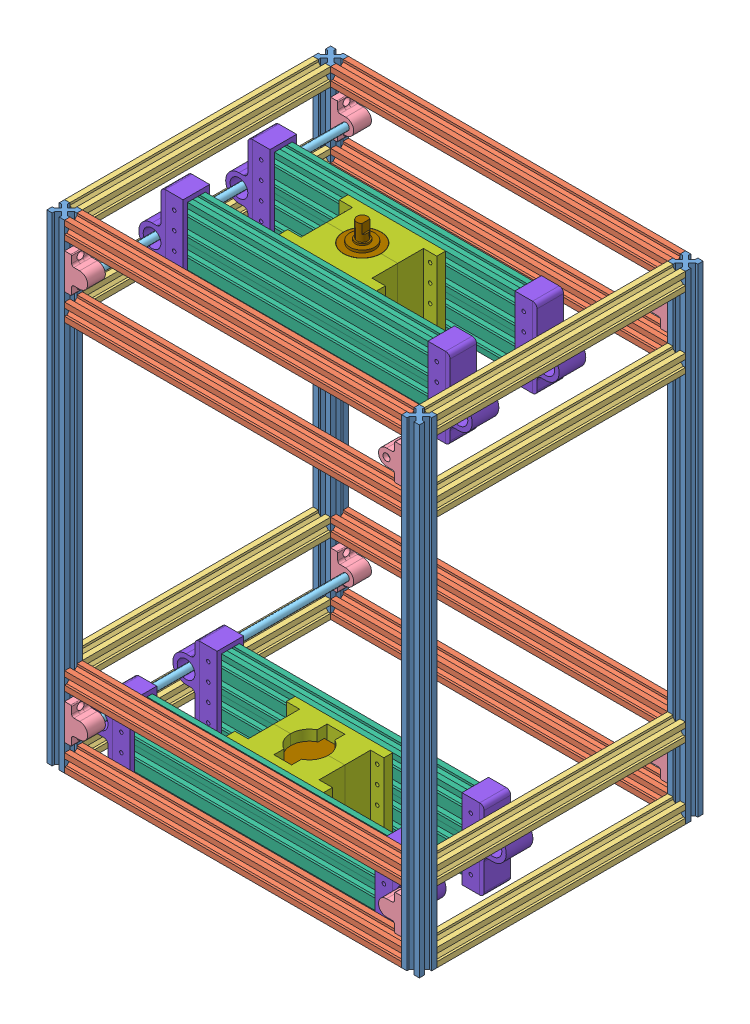
SolidWorks assembly chassis complété 1.1, configuration Défaut. Lengths in mm.
Overall size (420 586 320).
61 component instances, 9 part files, 54 mates.
Components (placement in the parent):
- module externe1.0-1: module externe1.0 [Défaut] at origin size (420 540 320)
  - base chassis horizontale-1: base chassis horizontale [Défaut] at (107.5488 34.6411 0) size (420 540 20)
    - profilé 540-1: profilé 540 [Défaut] at (-152.6624 -292.9685 550) size (20 540 20)
    - profilé 380-1: profilé 380 [Défaut] at (-152.6624 -272.9685 550) x (0 0 1) z (0 1 0) size (20 380 20)
    - profilé 380-2: profilé 380 [Défaut] at (227.3376 -212.9685 550) x (0 0 1) z (0 -1 0) size (20 380 20)
    - profilé 380-3: profilé 380 [Défaut] at (227.3376 227.0315 550) x (0 0 1) z (0 -1 0) size (20 380 20)
    - profilé 380-4: profilé 380 [Défaut] at (227.3376 147.0315 550) x (0 0 1) z (0 -1 0) size (20 380 20)
    - profilé 540-2: profilé 540 [Défaut] at (247.3376 -292.9685 530) x (0 0 -1) z (1 0 0) size (20 540 20)
  - profilé 280-1: profilé 280 [Défaut] at (-45.1136 -238.3275 550) x (0 1 0) z (1 0 0) size (20 280 20)
  - profilé 280-2: profilé 280 [Défaut] at (334.8864 -258.3275 830) x (-1 0 0) z (0 -1 0) size (20 280 20)
  - profilé 280-3: profilé 280 [Défaut] at (334.8864 281.6725 550) x (-1 0 0) z (0 1 0) size (20 280 20)
  - profilé 280-4: profilé 280 [Défaut] at (-65.1136 281.6725 550) x (-1 0 0) z (0 1 0) size (20 280 20)
  - base chassis horizontale-2: base chassis horizontale [Défaut] at (182.224 -11.296 300) x (-1 0 0) z (0 0 1) size (420 540 20)
    - profilé 540-1: profilé 540 [Défaut] at (-152.6624 -292.9685 550) size (20 540 20)
    - profilé 380-1: profilé 380 [Défaut] at (-152.6624 -272.9685 550) x (0 0 1) z (0 1 0) size (20 380 20)
    - profilé 380-2: profilé 380 [Défaut] at (227.3376 -212.9685 550) x (0 0 1) z (0 -1 0) size (20 380 20)
    - profilé 380-3: profilé 380 [Défaut] at (227.3376 227.0315 550) x (0 0 1) z (0 -1 0) size (20 380 20)
    - profilé 380-4: profilé 380 [Défaut] at (227.3376 147.0315 550) x (0 0 1) z (0 -1 0) size (20 380 20)
    - profilé 540-2: profilé 540 [Défaut] at (247.3376 -292.9685 530) x (0 0 -1) z (1 0 0) size (20 540 20)
  - profilé 280-5: profilé 280 [Défaut] at (-65.1136 -158.3275 550) x (-1 0 0) z (0 1 0) size (20 280 20)
  - profilé 280-6: profilé 280 [Défaut] at (354.8864 -178.3275 550) x (1 0 0) z (0 -1 0) size (20 280 20)
  - profilé 280-7: profilé 280 [Défaut] at (334.8864 181.6725 830) x (-1 0 0) z (0 -1 0) size (20 280 20)
  - profilé 280-8: profilé 280 [Défaut] at (-45.1136 181.6725 830) x (0 -1 0) z (1 0 0) size (20 280 20)
- support axe 8mm-1: support axe 8mm [Défaut] at (317.8864 -208.3275 850) x (0 -1 0) z (0 0 -1) size (40 26 20)
- support axe 8mm-3: support axe 8mm [Défaut] at (-28.1136 -208.3275 850) x (0 1 0) z (0 0 -1) size (40 26 20)
- support axe 8mm-4: support axe 8mm [Défaut] at (317.8864 -208.3275 530) x (0 1 0) z (0 0 1) size (40 26 20)
- support axe 8mm-5: support axe 8mm [Défaut] at (-28.1136 -208.3275 530) x (0 -1 0) z (0 0 1) size (40 26 20)
- support axe 8mm-6: support axe 8mm [Défaut] at (317.8864 231.6725 530) x (0 1 0) z (0 0 1) size (40 26 20)
- support axe 8mm-7: support axe 8mm [Défaut] at (-28.1136 231.6725 530) x (0 -1 0) z (0 0 1) size (40 26 20)
- support axe 8mm-8: support axe 8mm [Défaut] at (317.8864 231.6725 830) x (0 1 0) z (0 0 1) size (40 26 20)
- support axe 8mm-9: support axe 8mm [Défaut] at (-28.1136 231.6725 850) x (0 1 0) z (0 0 -1) size (40 26 20)
- axe 8mm-1: axe 8mm [Défaut] at (317.8864 -208.3275 535) x (-0.178456 0.983948 0) z (0 0 1) size (8 8 310)
- axe 8mm-2: axe 8mm [Défaut] at (-28.1136 -208.3275 535) size (8 8 310)
- axe 8mm-3: axe 8mm [Défaut] at (-28.1136 231.6725 535) size (8 8 310)
- axe 8mm-4: axe 8mm [Défaut] at (317.8864 231.6725 535) x (0.682458 0.730925 0) z (0 0 1) size (8 8 310)
- suspension1.0-1: suspension1.0 [Défaut] at (152.5638 -155.3507 385) x (0 1 0) z (0 0 1) size (90 376 64)
  - profilé 370-40-1: profilé 370-40 [Défaut] at (-82.9768 -150.3226 340) size (40 316 20)
  - profilé 370-40-2: profilé 370-40 [Défaut] at (-42.9768 -150.3226 340) size (40 316 20)
  - support moteur-2: support moteur [Défaut] at (-47.9768 7.6774 359.5) x (0 -1 0) z (-1 0 0) size (110 39 80)
  - fin profilé-1: fin profilé [Défaut] at (-62.9768 165.6774 330) x (-1 0 0) z (0 -1 0) size (90 30 50)
  - fin profilé-2: fin profilé [Défaut] at (-62.9768 -150.3226 330) x (-1 0 0) z (0 1 0) size (90 30 50)
- suspension1.0-2: suspension1.0 [Défaut] at (137.209 -155.3507 1143) x (0 1 0) z (0 0 -1) size (90 376 64)
  - profilé 370-40-1: profilé 370-40 [Défaut] at (-82.9768 -150.3226 340) size (40 316 20)
  - profilé 370-40-2: profilé 370-40 [Défaut] at (-42.9768 -150.3226 340) size (40 316 20)
  - support moteur-2: support moteur [Défaut] at (-47.9768 7.6774 359.5) x (0 -1 0) z (-1 0 0) size (110 39 80)
  - fin profilé-1: fin profilé [Défaut] at (-62.9768 165.6774 330) x (-1 0 0) z (0 -1 0) size (90 30 50)
  - fin profilé-2: fin profilé [Défaut] at (-62.9768 -150.3226 330) x (-1 0 0) z (0 1 0) size (90 30 50)
- moteur-1: moteur [Défaut] at (144.8864 -189.9275 764) x (1 0 0) z (0 -1 0) size (42 47 91.4)
- suspension1.0-3: suspension1.0 [Défaut] at (137.209 178.6957 325.3692) x (0 -1 0) z (0 0 1) size (90 376 64)
  - profilé 370-40-1: profilé 370-40 [Défaut] at (-82.9768 -150.3226 340) size (40 316 20)
  - profilé 370-40-2: profilé 370-40 [Défaut] at (-42.9768 -150.3226 340) size (40 316 20)
  - support moteur-2: support moteur [Défaut] at (-47.9768 7.6774 359.5) x (0 -1 0) z (-1 0 0) size (110 39 80)
  - fin profilé-1: fin profilé [Défaut] at (-62.9768 165.6774 330) x (-1 0 0) z (0 -1 0) size (90 30 50)
  - fin profilé-2: fin profilé [Défaut] at (-62.9768 -150.3226 330) x (-1 0 0) z (0 1 0) size (90 30 50)
- suspension1.0-4: suspension1.0 [Défaut] at (152.5638 178.6957 1083.3692) x (0 -1 0) z (0 0 -1) size (90 376 64)
  - profilé 370-40-1: profilé 370-40 [Défaut] at (-82.9768 -150.3226 340) size (40 316 20)
  - profilé 370-40-2: profilé 370-40 [Défaut] at (-42.9768 -150.3226 340) size (40 316 20)
  - support moteur-2: support moteur [Défaut] at (-47.9768 7.6774 359.5) x (0 -1 0) z (-1 0 0) size (110 39 80)
  - fin profilé-1: fin profilé [Défaut] at (-62.9768 165.6774 330) x (-1 0 0) z (0 -1 0) size (90 30 50)
  - fin profilé-2: fin profilé [Défaut] at (-62.9768 -150.3226 330) x (-1 0 0) z (0 1 0) size (90 30 50)
- moteur-2: moteur [Défaut] at (144.8864 213.2725 704.3692) x (-1 0 0) z (0 1 0) size (42 47 91.4)
Mates (geometry in assembly coordinates):
- Coïncidente1: coincident anti-aligned: plane of module externe1.0-1/base chassis horizontale-2/profilé 540-1 through (334.8864 -258.3275 850) normal (-1 0 0); plane of support axe 8mm-1 through (334.8864 -208.3275 830) normal (1 0 0)
- Coïncidente4: coincident anti-aligned: plane of module externe1.0-1/base chassis horizontale-2/profilé 540-2 through (-45.1136 -258.3275 830) normal (1 0 0); plane of support axe 8mm-3 through (-45.1136 -208.3275 830) normal (-1 0 0)
- Coïncidente7: coincident anti-aligned: plane of module externe1.0-1/base chassis horizontale-1/profilé 540-2 through (334.8864 281.6725 530) normal (-1 0 0); plane of support axe 8mm-4 through (334.8864 -208.3275 550) normal (1 0 0)
- Coïncidente8: coincident: line of module externe1.0-1/base chassis horizontale-1/profilé 540-2 through (334.8864 281.6725 530) axis (0 -1 0); point of support axe 8mm-4
- Distance3: distance = 10 mm anti-aligned: plane of support axe 8mm-4 through (317.8864 -188.3275 550) normal (0 1 0); plane of module externe1.0-1/base chassis horizontale-1/profilé 380-2 through (-45.1136 -178.3275 550) normal (0 -1 0)
- Coïncidente10: coincident anti-aligned: plane of module externe1.0-1/base chassis horizontale-1/profilé 540-1 through (-45.1136 281.6725 550) normal (1 0 0); plane of support axe 8mm-5 through (-45.1136 -208.3275 550) normal (-1 0 0)
- Coïncidente11: coincident: line of module externe1.0-1/base chassis horizontale-1/profilé 540-1 through (-45.1136 281.6725 530) axis (0 -1 0); point of support axe 8mm-5
- Distance4: distance = 10 mm anti-aligned: plane of support axe 8mm-5 through (-28.1136 -228.3275 550) normal (0 -1 0); plane of module externe1.0-1/base chassis horizontale-1/profilé 380-1 through (334.8864 -238.3275 550) normal (0 1 0)
- Coïncidente15: coincident anti-aligned: plane of module externe1.0-1/base chassis horizontale-1/profilé 540-2 through (334.8864 281.6725 530) normal (-1 0 0); plane of support axe 8mm-6 through (334.8864 231.6725 550) normal (1 0 0)
- Coïncidente16: coincident: line of module externe1.0-1/base chassis horizontale-1/profilé 540-2 through (334.8864 281.6725 530) axis (0 -1 0); point of support axe 8mm-6
- Coïncidente18: coincident anti-aligned: plane of module externe1.0-1/base chassis horizontale-1/profilé 540-1 through (-45.1136 281.6725 550) normal (1 0 0); plane of support axe 8mm-7 through (-45.1136 231.6725 550) normal (-1 0 0)
- Coïncidente19: coincident: line of module externe1.0-1/base chassis horizontale-1/profilé 540-1 through (-45.1136 281.6725 530) axis (0 -1 0); point of support axe 8mm-7
- Distance6: distance = 10 mm anti-aligned: plane of support axe 8mm-7 through (-28.1136 251.6725 550) normal (0 1 0); plane of module externe1.0-1/base chassis horizontale-1/profilé 380-3 through (-45.1136 261.6725 550) normal (0 -1 0)
- Coïncidente21: coincident anti-aligned: plane of module externe1.0-1/base chassis horizontale-2/profilé 540-1 through (334.8864 -258.3275 850) normal (-1 0 0); plane of support axe 8mm-8 through (334.8864 231.6725 850) normal (1 0 0)
- Coïncidente22: coincident: line of module externe1.0-1/base chassis horizontale-2/profilé 540-1 through (334.8864 -258.3275 850) axis (0 1 0); point of support axe 8mm-8
- Distance7: distance = 10 mm anti-aligned: plane of module externe1.0-1/base chassis horizontale-2/profilé 380-1 through (-45.1136 261.6725 850) normal (0 -1 0); plane of support axe 8mm-8 through (317.8864 251.6725 850) normal (0 1 0)
- Coïncidente24: coincident anti-aligned: plane of module externe1.0-1/base chassis horizontale-2/profilé 540-2 through (-45.1136 -258.3275 830) normal (1 0 0); plane of support axe 8mm-9 through (-45.1136 231.6725 830) normal (-1 0 0)
- Coaxiale2: concentric aligned: cylinder of support axe 8mm-5 through (-28.1136 -208.3275 550) axis (0 0 -1) radius 4; cylinder of axe 8mm-2 through (-28.1136 -208.3275 845) axis (0 0 -1) radius 4
- DistanceLimite1: limit distance = 150 mm anti-aligned: plane of support axe 8mm-4 through (317.8864 -208.3275 550) normal (0 0 1); plane of suspension1.0-1/fin profilé-2 through (282.8864 -263.3275 700) normal (0 0 -1)
- Coaxiale9: concentric aligned: cylinder of axe 8mm-2 through (-28.1136 -208.3275 845) axis (0 0 -1) radius 4; cylinder of suspension1.0-2/fin profilé-2 through (-28.1136 -208.3275 828) axis (0 0 -1) radius 10
- Coaxiale11: concentric anti-aligned: cylinder of axe 8mm-1 through (317.8864 -208.3275 845) axis (0 0 -1) radius 4; cylinder of suspension1.0-1/fin profilé-2 through (317.8864 -208.3275 700) axis (0 0 1) radius 10
- Parallèle1: parallel anti-aligned: plane of module externe1.0-1/profilé 280-2 through (334.8864 -258.3275 550) normal (-1 0 0); plane of suspension1.0-1/fin profilé-2 through (307.8864 -218.3275 700) normal (1 0 0)
- Coïncidente34: coincident anti-aligned: plane of suspension1.0-1/support moteur-2 through (144.8864 -258.3275 764) normal (0 0 1); plane of suspension1.0-2/support moteur-2 through (144.8864 -258.3275 764) normal (0 0 -1)
- Coaxiale12: concentric aligned: cylinder of suspension1.0-2/support moteur-2 through (144.8864 -258.3275 764) axis (0 1 0) radius 21.25; cylinder of moteur-1 through (144.8864 -211.9275 764) axis (0 1 0) radius 21
- Coïncidente35: coincident aligned: plane of suspension1.0-1/support moteur-2 through (144.8864 -258.3275 744.5) normal (0 -1 0); plane of moteur-1 through (144.8864 -258.3275 764) normal (0 -1 0)
- Coaxiale14: concentric anti-aligned: cylinder of axe 8mm-3 through (-28.1136 231.6725 845) axis (0 0 -1) radius 4; cylinder of suspension1.0-3/fin profilé-2 through (-28.1136 231.6725 640.3692) axis (0 0 1) radius 10
- DistanceLimite2: limit distance = 90.3692 mm anti-aligned: plane of suspension1.0-3/fin profilé-2 through (6.8864 286.6725 640.3692) normal (0 0 -1); plane of support axe 8mm-7 through (-28.1136 231.6725 550) normal (0 0 1)
- Parallèle2: parallel anti-aligned: plane of suspension1.0-1/support moteur-2 through (144.8864 -178.3275 734) normal (0 0 1); plane of moteur-1 through (144.8864 -199.9275 738) normal (0 0 -1)
- Coaxiale15: concentric anti-aligned: cylinder of axe 8mm-3 through (-28.1136 231.6725 845) axis (0 0 -1) radius 4; cylinder of suspension1.0-4/fin profilé-1 through (7.356 231.6725 861.4726) axis (0 0 1) radius 10
- Coaxiale16: concentric aligned: cylinder of suspension1.0-3/support moteur-2 through (63.2517 386.8543 704.3692) axis (0.686983 -0.726673 0) radius 21.25; cylinder of moteur-2 through (63.2517 386.8543 704.3692) axis (0.686983 -0.726673 0) radius 21
- Parallèle3: parallel anti-aligned: plane of suspension1.0-3/support moteur-2 through (118.2104 328.7205 674.3692) normal (0 0 1); plane of moteur-2 through (103.3715 344.4166 678.3692) normal (0 0 -1)
- Coïncidente40: coincident anti-aligned: plane of suspension1.0-3/support moteur-2 through (63.2517 386.8543 704.3692) normal (0 0 1); plane of suspension1.0-4/support moteur-2 through (98.7213 386.8543 827.4726) normal (0 0 -1)
- Coïncidente41: coincident aligned: plane of suspension1.0-3/support moteur-2 through (63.2517 386.8543 684.8692) normal (-0.686983 0.726673 0); plane of moteur-2 through (63.2517 386.8543 704.3692) normal (-0.686983 0.726673 0)
- Coïncidente42: coincident aligned: plane of module externe1.0-1 through (0 0 0) normal (0 0 1)
- Coïncidente43: coincident aligned: plane of module externe1.0-1 through (0 0 0) normal (0 1 0)
- Coïncidente44: coincident aligned: plane of module externe1.0-1 through (0 0 0) normal (1 0 0)
- Coïncidente45: coincident anti-aligned: plane of support axe 8mm-5 through (-28.1136 -208.3275 535) normal (0 0 1); plane of axe 8mm-2 through (-28.1136 -208.3275 535) normal (0 0 -1)
- Coïncidente46: coincident: line of module externe1.0-1/base chassis horizontale-2/profilé 540-2 through (-45.1136 -258.3275 830) axis (0 1 0); point of support axe 8mm-3
- Coïncidente47: coincident: line of module externe1.0-1/base chassis horizontale-2/profilé 540-2 through (-45.1136 -258.3275 850) axis (0 1 0); point of support axe 8mm-3
- Distance9: distance = 10 mm anti-aligned: plane of support axe 8mm-3 through (-28.1136 -188.3275 830) normal (0 1 0); plane of module externe1.0-1/base chassis horizontale-2/profilé 380-4 through (334.8864 -178.3275 850) normal (0 -1 0)
- Coïncidente49: coincident anti-aligned: circle of support axe 8mm-4; circle of axe 8mm-1
- Coïncidente50: coincident: line of module externe1.0-1/base chassis horizontale-2/profilé 540-1 through (334.8864 -258.3275 830) axis (0 1 0); point of support axe 8mm-1
- Coïncidente53: coincident: line of module externe1.0-1/base chassis horizontale-2/profilé 540-1 through (334.8864 -258.3275 850) axis (0 1 0); point of support axe 8mm-1
- Distance10: distance = 10 mm anti-aligned: plane of support axe 8mm-1 through (317.8864 -188.3275 830) normal (0 1 0); plane of module externe1.0-1/base chassis horizontale-2/profilé 380-4 through (334.8864 -178.3275 850) normal (0 -1 0)
- Coaxiale18: concentric aligned: cylinder of support axe 8mm-4 through (317.8864 -208.3275 550) axis (0 0 -1) radius 4; cylinder of axe 8mm-1 through (317.8864 -208.3275 845) axis (0 0 -1) radius 4
- Coaxiale19: concentric aligned: cylinder of support axe 8mm-6 through (317.8864 231.6725 550) axis (0 0 -1) radius 4; cylinder of axe 8mm-4 through (317.8864 231.6725 845) axis (0 0 -1) radius 4
- Coïncidente58: coincident anti-aligned: plane of support axe 8mm-6 through (317.8864 231.6725 535) normal (0 0 1); plane of axe 8mm-4 through (317.8864 231.6725 535) normal (0 0 -1)
- Distance11: distance = 10 mm anti-aligned: plane of support axe 8mm-6 through (317.8864 251.6725 550) normal (0 1 0); plane of module externe1.0-1/base chassis horizontale-1/profilé 380-3 through (-45.1136 261.6725 550) normal (0 -1 0)
- Coïncidente61: coincident anti-aligned: plane of support axe 8mm-7 through (-28.1136 231.6725 535) normal (0 0 1); plane of axe 8mm-3 through (-28.1136 231.6725 535) normal (0 0 -1)
- Coïncidente67: coincident: line of module externe1.0-1/base chassis horizontale-2/profilé 540-2 through (-45.1136 -258.3275 850) axis (0 1 0); point of support axe 8mm-9
- Coïncidente70: coincident: line of module externe1.0-1/base chassis horizontale-2/profilé 540-2 through (-45.1136 -258.3275 850) axis (0 1 0); point of support axe 8mm-9
- Distance12: distance = 10 mm anti-aligned: plane of support axe 8mm-9 through (-28.1136 211.6725 830) normal (0 -1 0); plane of module externe1.0-1/base chassis horizontale-2/profilé 380-2 through (334.8864 201.6725 850) normal (0 1 0)
- Coaxiale20: concentric anti-aligned: cylinder of support axe 8mm-9 through (-28.1136 231.6725 830) axis (0 0 1) radius 4; cylinder of axe 8mm-3 through (-28.1136 231.6725 845) axis (0 0 -1) radius 4
- Parallèle6: parallel aligned: plane of module externe1.0-1/base chassis horizontale-2/profilé 380-1 through (-45.1136 281.6725 850) normal (0 1 0); plane of suspension1.0-4/support moteur-2 through (144.8864 281.6725 723.8692) normal (0 1 0)
